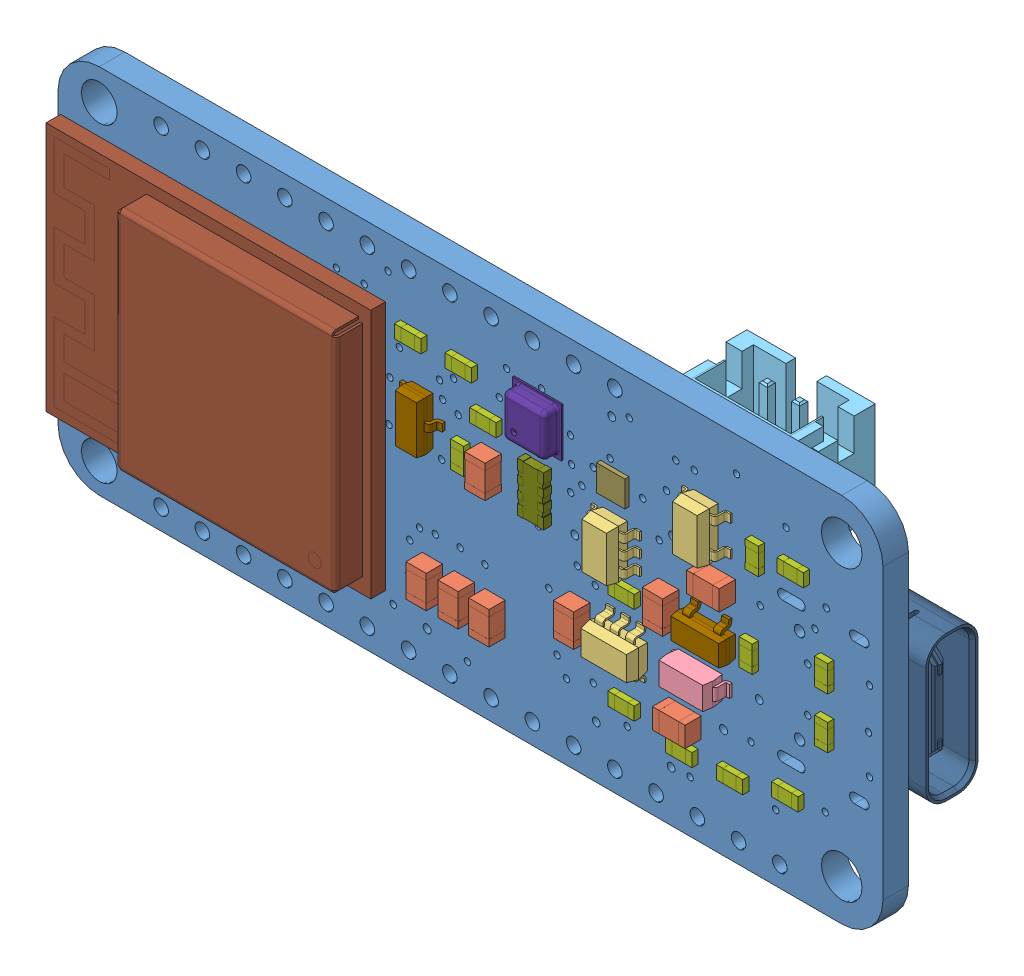
SolidWorks assembly 5300 ESP32-S2 TFT Feather, configuration Default. Lengths in mm.
Overall size (51.88 22.86 8.92).
44 component instances, 17 part files, 0 mates.
Components (placement in the parent):
- 5300 ESP32-S2 TFT Feather.step-1: 5300 ESP32-S2 TFT Feather.step [Default] at origin size (51.88 22.86 8.92)
  - PCB Component.step-1: PCB Component.step [Default] at origin size (51.88 22.86 8.92)
    - Board.step-1: Board.step [Default] at origin size (50.8 22.86 1.57)
    - 10uF.step-1: 10uF.step [Default] at (37.603 11.816 1.57) x (0 1 0) z (0 0 1) size (2 1.25 1)
    - 10uF.step-2: 10uF.step [Default] at (25.017 5.915 1.57) x (0 1 0) z (0 0 1) size (2 1.25 1)
    - 10uF.step-3: 10uF.step [Default] at (40.716 14.478 1.57) size (2 1.25 1)
    - 10uF.step-4: 10uF.step [Default] at (26.911 5.906 1.57) x (0 1 0) z (0 0 1) size (2 1.25 1)
    - 10uF.step-5: 10uF.step [Default] at (38.608 6.147 1.57) size (2 1.25 1)
    - 10uF.step-6: 10uF.step [Default] at (23.05 5.906 1.57) x (0 1 0) z (0 0 1) size (2 1.25 1)
    - 10uF.step-7: 10uF.step [Default] at (32.131 8.382 1.57) x (0 1 0) z (0 0 1) size (2 1.25 1)
    - 10uF.step-8: 10uF.step [Default] at (26.67 13.589 1.57) x (0 1 0) z (0 0 1) size (2 1.25 1)
    - AP2112-3.3.step-1: AP2112-3.3.step [Default] at (35.001 8.382 1.57) x (-1 0 0) z (0 0 1) size (3 3 1.4)
    - AP2112-3.3.step-2: AP2112-3.3.step [Default] at (40.005 17.323 1.57) x (0 -1 0) z (0 0 1) size (3 3 1.4)
    - AP2112-3.3.step-3: AP2112-3.3.step [Default] at (34.417 13.589 1.57) x (0 1 0) z (0 0 1) size (3 3 1.4)
    - MBR540.step-1: MBR540.step [Default] at (39.7 9.093 1.57) size (3.6 1.4 1.35)
    - JSTPH.step-1: JSTPH.step [Default] at (40.005 19.304 0) x (-1 0 0) z (0 0 -1) size (7.9 8.6 4.8)
    - RED.step-1: RED.step [Default] at (49.022 5.461 0) x (0 -1 0) z (0 0 -1) size (0.79 1.6 0.71)
    - RED.step-2: RED.step [Default] at (49.276 17.399 0) x (0 1 0) z (0 0 -1) size (0.79 1.6 0.71)
    - 1uF.step-1: 1uF.step [Default] at (45.136 5.41 1.57) x (-1 0 0) z (0 0 1) size (1.62 0.81 0.38)
    - 1uF.step-2: 1uF.step [Default] at (45.466 17.526 1.57) size (1.62 0.81 0.38)
    - 1uF.step-3: 1uF.step [Default] at (35.052 11.163 1.57) size (1.62 0.81 0.38)
    - 1uF.step-4: 1uF.step [Default] at (42.723 11.735 1.57) x (0 -1 0) z (0 0 1) size (1.62 0.81 0.38)
    - 1uF.step-5: 1uF.step [Default] at (41.732 4.623 1.57) size (1.62 0.81 0.38)
    - 1uF.step-6: 1uF.step [Default] at (43.104 17.145 1.57) x (0 1 0) z (0 0 1) size (1.62 0.81 0.38)
    - 1uF.step-7: 1uF.step [Default] at (47.371 9.881 1.57) x (0 -1 0) z (0 0 1) size (1.62 0.81 0.38)
    - 1uF.step-8: 1uF.step [Default] at (47.371 13.018 1.57) x (0 1 0) z (0 0 1) size (1.62 0.81 0.38)
    - 1uF.step-9: 1uF.step [Default] at (38.608 4.508 1.57) x (-1 0 0) z (0 0 1) size (1.62 0.81 0.38)
    - 1uF.step-10: 1uF.step [Default] at (21.908 18.224 1.57) size (1.62 0.81 0.38)
    - 1uF.step-11: 1uF.step [Default] at (25.019 18.224 1.57) size (1.62 0.81 0.38)
    - 1uF.step-12: 1uF.step [Default] at (35.052 5.207 1.57) x (-1 0 0) z (0 0 1) size (1.62 0.81 0.38)
    - 1uF.step-13: 1uF.step [Default] at (24.956 13.398 1.57) x (0 1 0) z (0 0 1) size (1.62 0.81 0.38)
    - 1uF.step-14: 1uF.step [Default] at (26.543 16.066 1.57) x (-1 0 0) z (0 0 1) size (1.62 0.81 0.38)
    - KMR2.step-1: KMR2.step [Default] at (41.783 6.223 0) x (0 1 0) z (0 0 -1) size (4.6 2.8 1.94)
    - KMR2.step-2: KMR2.step [Default] at (37.084 6.223 0) x (0 1 0) z (0 0 -1) size (4.6 2.8 1.94)
    - BSS138.step-1: BSS138.step [Default] at (40.335 11.633 1.57) x (-1 0 0) z (0 0 1) size (3.04 2.64 1.12)
    - BSS138.step-2: BSS138.step [Default] at (22.542 14.351 1.57) x (0 -1 0) z (0 0 1) size (3.04 2.64 1.12)
    - USB C.step-1: USB C.step [Default] at (48.133 11.43 0) x (0 -1 0) z (0 0 -1) size (8.94 7.9 4.2)
    - ESP32-S2-MODULE_MINI.step-1: ESP32-S2-MODULE_MINI.step [Default] at (10.16 11.43 1.57) x (0 1 0) z (0 0 1) size (15.4 20 2.55)
    - LC709203F_MH.step-1: LC709203F_MH.step [Default] at (34.29 16.51 1.57) size (1.75 1.6 0.51)
    - STEMMA_I2C_QTRA.step-1: STEMMA_I2C_QTRA.step [Default] at (39.878 11.557 0) x (1 0 0) z (0 0 -1) size (6 3.6 4.3)
    - WS2812B_SK6805_1515.step-1: WS2812B_SK6805_1515.step [Default] at (45.593 17.526 0) x (0 1 0) z (0 0 -1) size (1.5 1.5 0.48)
    - DISP_LCD_GENERIC_SPI_1.14IN_240X135_WRAPUNDER.step-1: DISP_LCD_GENERIC_SPI_1.14IN_240X135_WRAPUNDER.step [Default] at (4.318 11.43 0) x (0 1 0) z (0 0 -1) size (17.55 31.66 1.52)
    - 10K.step-1: 10K.step [Default] at (29.591 13.843 1.57) x (0 -1 0) z (0 0 1) size (3.05 1.6 0.5)
    - BME680.step-1: BME680.step [Default] at (29.591 17.653 1.57) size (3 3 0.93)
